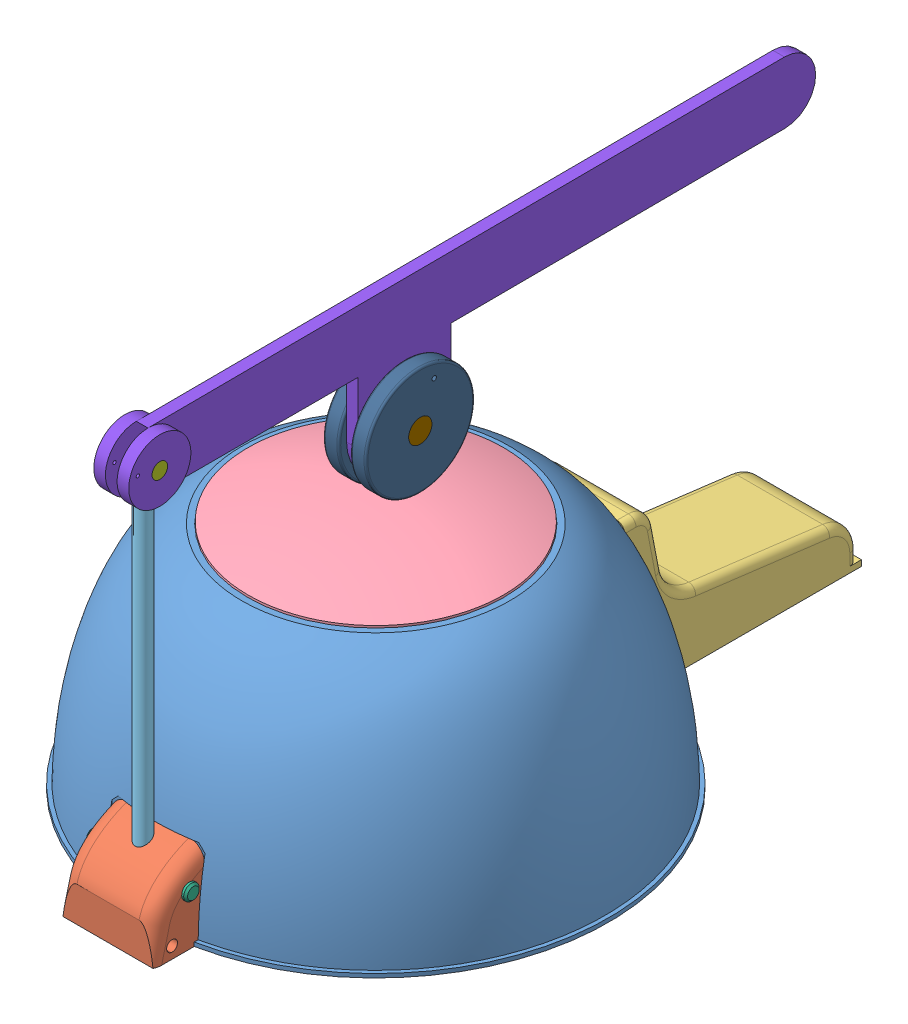
SolidWorks assembly 50  Assemblage, configuration Défaut. Lengths in mm.
Overall size (120 112.84 182.16).
12 component instances, 10 part files, 20 mates.
Components (placement in the parent):
- 1  Coupelle extérieure-1: 1  Coupelle extérieure [Défaut] at (42.4148 -15.5563 120.5) size (120 60 121.39)
- 2  Fixation arrière-1: 2  Fixation arrière [Défaut] at (-29.5852 -15.5563 177.5) x (0 0 -1) z (1 0 0) size (14.98 22.19 24.78)
- 3  Fixation avant-1: 3  Fixation avant [Défaut] at (-30.4444 -15.7632 69.5) x (0 0 -1) z (1 0 0) size (61 39.79 26)
- 4  Piston-1: 4  Piston [Défaut] at (-17.5852 33.9447 120.5) x (-0.987571 0 0.157173) z (-0.157173 0 -0.987571) size (65.8 16 65.8)
- 51  Assemblage-1: 51  Assemblage [Défaut] at (122.4148 13.8625 229.7525) x (0 0 1) z (-1 0 0) size (4 94 26)
  - 5  Tige de rappel-1: 5  Tige de rappel [Défaut] at (-51.2525 -16.4187 140) size (4 90 4)
  - 6  Tige transversale Bas-1: 6  Tige transversale Bas [Défaut] at (-49.2525 -16.4187 127) size (4 4 26)
  - 8 Tige transversale Haut-1: 8 Tige transversale Haut [Défaut] at (-49.2525 73.5813 144.6486) x (0 0 -1) z (1 0 0) size (9 4 4)
- 7  Levier-1: 7  Levier [Défaut] at (-19.2338 80.3433 -3.5369) x (0 0.004888 -0.999988) z (1 0 0) size (180 44 9)
- 10  Axe de roulettes-1: 10  Axe de roulettes [Défaut] at (-23.2338 63.7666 114.3835) size (11 6 6)
- 9  Roulettes-1: 9  Roulettes [Défaut] at (-12.2338 63.7666 114.3835) x (0 -0.542815 0.839852) z (-1 0 0) size (28 28 4)
- 9  Roulettes-2: 9  Roulettes [Défaut] at (-19.2338 63.7666 114.3835) x (0 0 1) z (-1 0 0) size (28 28 4)
Mates (geometry in assembly coordinates):
- Coïncidente1: coincident anti-aligned: plane of 1  Coupelle extérieure-1 through (42.4148 -15.5563 176.5) normal (0 0 1); plane of 2  Fixation arrière-1 through (-5.5852 5.4437 176.5) normal (0 0 -1)
- Coïncidente2: coincident aligned: plane of 1  Coupelle extérieure-1 through (-75.5852 -15.5563 120.5) normal (0 -1 0); plane of 2  Fixation arrière-1 through (-5.5852 -15.5563 176.5) normal (0 -1 0)
- Coïncidente3: coincident anti-aligned: plane of 1  Coupelle extérieure-1 through (-5.5852 -16.5563 176.5) normal (-1 0 0); plane of 2  Fixation arrière-1 through (-5.5852 0.9634 184.4886) normal (1 0 0)
- Coïncidente4: coincident anti-aligned: plane of 1  Coupelle extérieure-1 through (42.4148 -15.5563 69.5) normal (0 0 -1); plane of 3  Fixation avant-1 through (-4.4444 24.2368 69.5) normal (0 0 1)
- Coïncidente5: coincident anti-aligned: plane of 1  Coupelle extérieure-1 through (-4.4444 23.4437 69.5) normal (-1 0 0); plane of 3  Fixation avant-1 through (-4.4444 11.0983 49.7454) normal (1 0 0)
- Coïncidente6: coincident aligned: plane of 1  Coupelle extérieure-1 through (-75.5852 -15.5563 120.5) normal (0 -1 0); plane of 3  Fixation avant-1 through (-4.4444 -15.5563 8.5) normal (0 -1 0)
- Parallèle1: parallel anti-aligned: line of 2  Fixation arrière-1 through (-5.9959 -15.5563 189.5) axis (-1 0 0); cylinder of 51  Assemblage-1/6  Tige transversale Bas-1 through (-30.5852 -2.5563 180.5) axis (1 0 0) radius 2
- Coaxiale3: concentric aligned: cylinder of 2  Fixation arrière-1 through (-29.8621 -2.5563 180.5) axis (1 0 0) radius 2; cylinder of 51  Assemblage-1/6  Tige transversale Bas-1 through (-30.5852 -2.5563 180.5) axis (1 0 0) radius 2
- Coaxiale1: concentric anti-aligned: cylinder of 1  Coupelle extérieure-1 through (-17.5852 10.4437 120.5) axis (0 1 0) radius 33; cylinder of 4  Piston-1 through (-17.5852 33.9447 120.5) axis (0 -1 0) radius 32.9
- Coaxiale4: concentric anti-aligned: cylinder of 51  Assemblage-1/8 Tige transversale Haut-1 through (-13.2338 87.4437 180.5) axis (-1 0 0) radius 2; cylinder of 7  Levier-1 through (-22.2338 87.4437 180.5) axis (1 0 0) radius 2
- Coïncidente7: coincident aligned: plane of 51  Assemblage-1/8 Tige transversale Haut-1 through (-13.2338 87.4437 180.5) normal (1 0 0); plane of 7  Levier-1 through (-13.2338 87.4437 180.5) normal (1 0 0)
- Coaxiale2: concentric aligned: cylinder of 2  Fixation arrière-1 through (-17.5852 5.7206 180.5) axis (0 -1 0) radius 2; cylinder of 51  Assemblage-1/5  Tige de rappel-1 through (-17.5852 -2.5563 180.5) axis (0 -1 0) radius 2
- Coaxiale5: concentric aligned: cylinder of 7  Levier-1 through (-16.2338 63.7666 114.3835) axis (-1 0 0) radius 3; cylinder of 10  Axe de roulettes-1 through (-12.2338 63.7666 114.3835) axis (-1 0 0) radius 3
- Distance5: distance = 4 mm aligned: plane of 10  Axe de roulettes-1 through (-12.2338 63.7666 114.3835) normal (1 0 0); plane of 7  Levier-1 through (-16.2338 63.7666 114.3835) normal (1 0 0)
- Coaxiale6: concentric anti-aligned: cylinder of 10  Axe de roulettes-1 through (-12.2338 63.7666 114.3835) axis (-1 0 0) radius 3; cylinder of 9  Roulettes-1 through (-16.2338 63.7666 114.3835) axis (1 0 0) radius 3
- Coïncidente14: coincident aligned: plane of 10  Axe de roulettes-1 through (-12.2338 63.7666 114.3835) normal (1 0 0); plane of 9  Roulettes-1 through (-12.2338 63.7666 114.3835) normal (1 0 0)
- Coaxiale7: concentric anti-aligned: cylinder of 10  Axe de roulettes-1 through (-12.2338 63.7666 114.3835) axis (-1 0 0) radius 3; cylinder of 9  Roulettes-2 through (-23.2338 63.7666 114.3835) axis (1 0 0) radius 3
- Coïncidente15: coincident aligned: plane of 10  Axe de roulettes-1 through (-23.2338 63.7666 114.3835) normal (-1 0 0); plane of 9  Roulettes-2 through (-23.2338 63.7666 114.3835) normal (-1 0 0)
- AngleLimite3: limit planar angle = 1.570796 rad aligned: plane of 7  Levier-1 through (-16.2338 79.7078 126.4615) normal (0 -1 0); plane of 2  Fixation arrière-1 through (-5.5852 -15.5563 189.5) normal (0 0 1); plane of 1  Coupelle extérieure-1 through (-5.5852 -16.5563 176.5) normal (-1 0 0)
- Tangent5: tangent: face of 4  Piston-1; cylinder of 9  Roulettes-1 through (-16.2338 63.7666 114.3835) axis (1 0 0) radius 14
